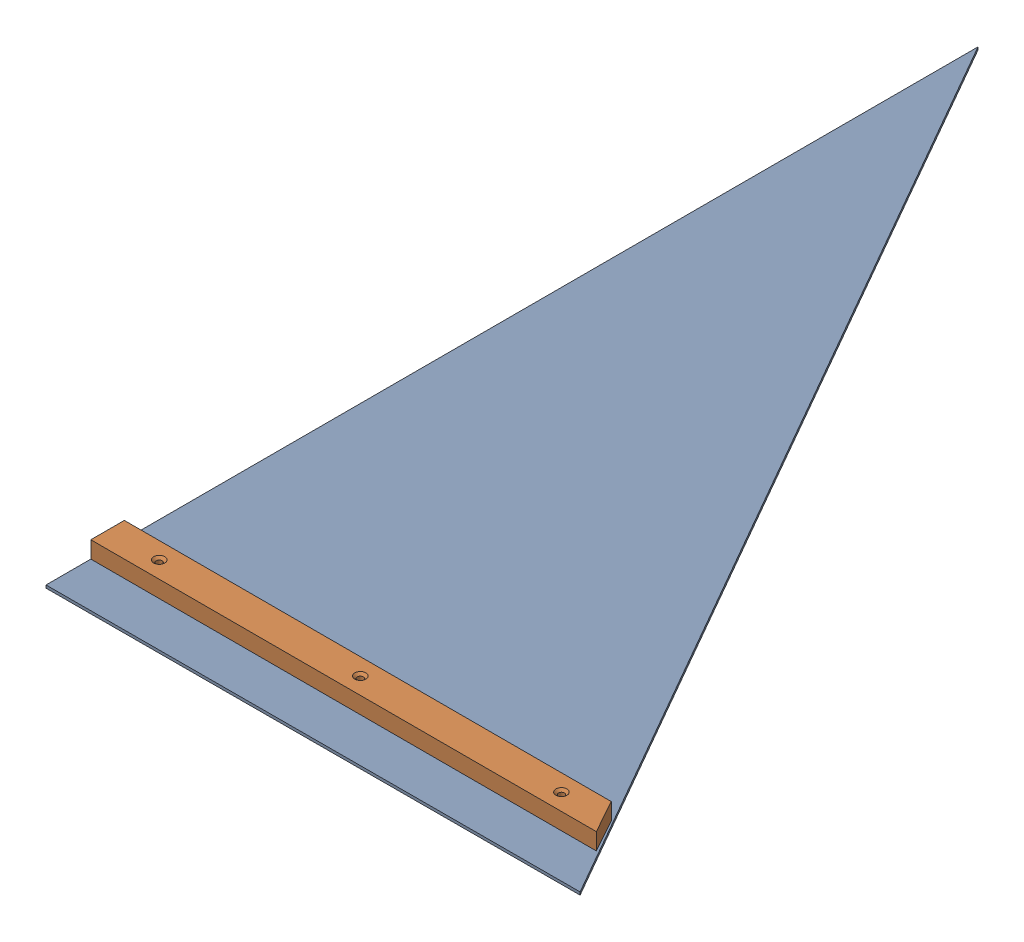
SolidWorks assembly GE-16187_ASM, configuration Default. Lengths in mm.
Overall size (605.76 22.23 1059.46).
2 component instances, 2 part files, 0 mates.
Components (placement in the parent):
- GE-16144-1: GE-16144 [Default] at origin size (605.76 3.17 1059.46)
- GE-16181-1: GE-16181 [Default] at (0 3.175 1008.5242) x (1 0 0) z (0 1 0) size (574.68 38.1 19.05)
